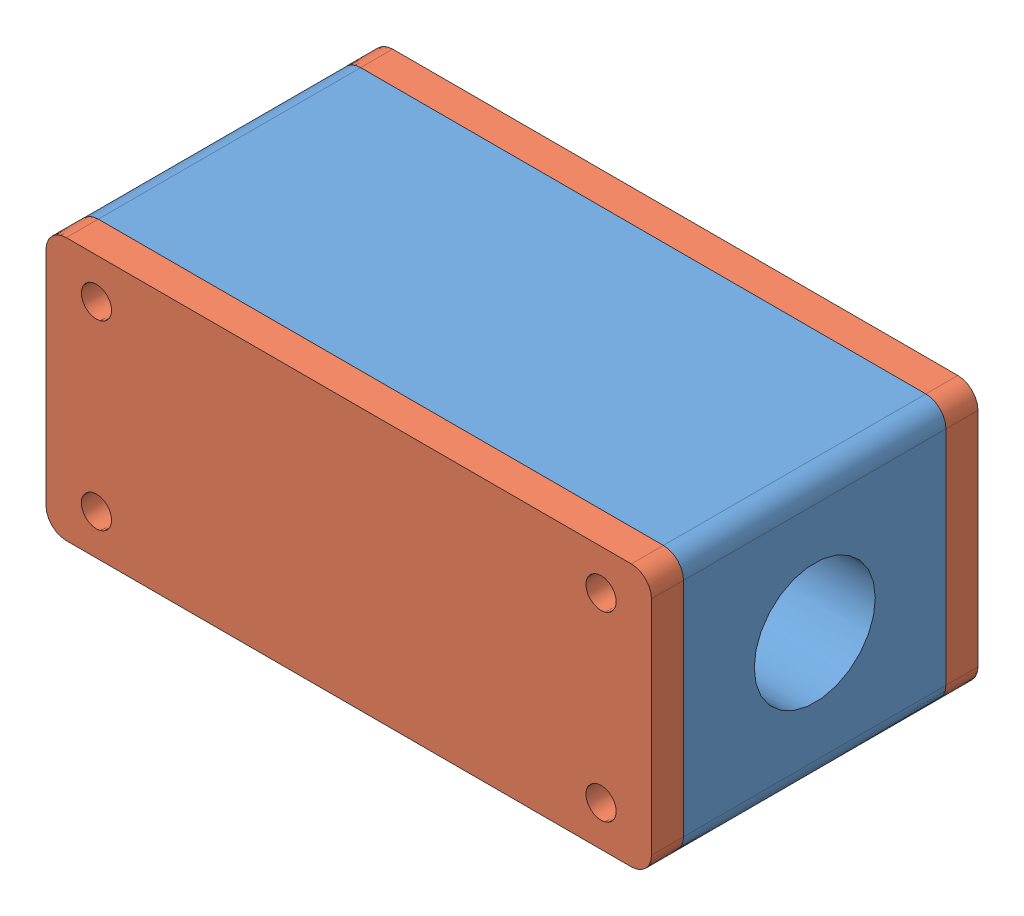
SolidWorks assembly UOM20-4P010, configuration Default. Lengths in mm.
Overall size (60 26 32.35).
6 component instances, 5 part files, 14 mates.
Components (placement in the parent):
- Block1-1: Block1 [Default] at (-59.7244 -6.4427 -4.0467) size (60 26 26)
- spring plate-1: spring plate [Default] at (-59.7244 -6.4427 -4.0467) x (-1 0 0) z (0 0 -1) size (60 26 3.17)
- spring plate-2: spring plate [Default] at (0.2756 -6.4427 21.9533) size (60 26 3.17)
- leadnut-1: leadnut [Default] at (-36.9744 6.5573 8.9533) x (-1 0 0) z (0 -1 0) size (10 24 10.5)
- 9434K135_MUSIC-WIRE STEEL COMPRESSION SPRINGS-1: 9434K135_MUSIC-WIRE STEEL COMPRESSION SPRINGS [9434K135] at (-41.4744 6.4644 9.0297) x (0 -1 0) z (0 0 1) size (15.72 32.66 15.84)
- guide block-1: guide block [Default] at (-41.4744 -1.4427 21.9533) x (0 1 0) z (-1 0 0) size (16 26 7)
Mates (geometry in assembly coordinates):
- Coincident3: coincident anti-aligned: plane of Block1-1 through (-57.7244 17.5573 21.9533) normal (0 0 1); plane of spring plate-2 through (0.2756 -6.4427 21.9533) normal (0 0 -1)
- Coincident4: coincident aligned: plane of Block1-1 through (-57.7244 19.5573 21.9533) normal (0 1 0); plane of spring plate-2 through (0.2756 19.5573 25.1283) normal (0 1 0)
- Coincident5: coincident aligned: plane of Block1-1 through (-59.7244 -4.4427 21.9533) normal (-1 0 0); plane of spring plate-2 through (-59.7244 -6.4427 25.1283) normal (-1 0 0)
- Coincident6: coincident aligned: plane of Block1-1 through (-57.7244 19.5573 21.9533) normal (0 1 0); plane of spring plate-1 through (-59.7244 19.5573 -7.2217) normal (0 1 0)
- Coincident7: coincident aligned: plane of Block1-1 through (-59.7244 -4.4427 21.9533) normal (-1 0 0); plane of spring plate-1 through (-59.7244 -6.4427 -7.2217) normal (-1 0 0)
- Coincident8: coincident anti-aligned: plane of Block1-1 through (-57.7244 17.5573 -4.0467) normal (0 0 -1); plane of spring plate-1 through (-59.7244 -6.4427 -4.0467) normal (0 0 1)
- Concentric1: concentric aligned: cylinder of Block1-1 through (-59.7244 6.5573 8.9533) axis (1 0 0) radius 6; cylinder of leadnut-1 through (-9.7481 6.5573 8.9533) axis (1 0 0) radius 5
- Parallel2: parallel aligned: plane of Block1-1 through (-57.7244 -6.4427 21.9533) normal (0 -1 0); plane of leadnut-1 through (-36.9744 1.3073 -5.9891) normal (0 -1 0)
- Coincident12: coincident anti-aligned: plane of Block1-1 through (-9.7244 14.5573 21.9533) normal (-1 0 0); plane of 9434K135_MUSIC-WIRE STEEL COMPRESSION SPRINGS-1 through (-9.7244 14.0844 1.4096) normal (1 0 0)
- Coincident13: coincident anti-aligned: plane of leadnut-1 through (-41.4744 6.5573 3.9533) normal (1 0 0); plane of 9434K135_MUSIC-WIRE STEEL COMPRESSION SPRINGS-1 through (-41.4744 14.0844 1.4096) normal (-1 0 0)
- Lock1: lock: unknown of leadnut-1; unknown of 9434K135_MUSIC-WIRE STEEL COMPRESSION SPRINGS-1
- Coincident14: coincident anti-aligned: plane of leadnut-1 through (-44.9744 6.5573 -3.0467) normal (-1 0 0); plane of guide block-1 through (-44.9744 -1.4427 21.9533) normal (1 0 0)
- Concentric2: concentric aligned: cylinder of leadnut-1 through (-9.7481 6.5573 8.9533) axis (1 0 0) radius 5; cylinder of guide block-1 through (-47.4744 6.5573 8.9533) axis (1 0 0) radius 5
- Perpendicular1: perpendicular: plane of spring plate-1 through (-59.7244 -6.4427 -7.2217) normal (0 0 -1); plane of guide block-1 through (-44.9744 -1.4427 21.9533) normal (0 -1 0)
